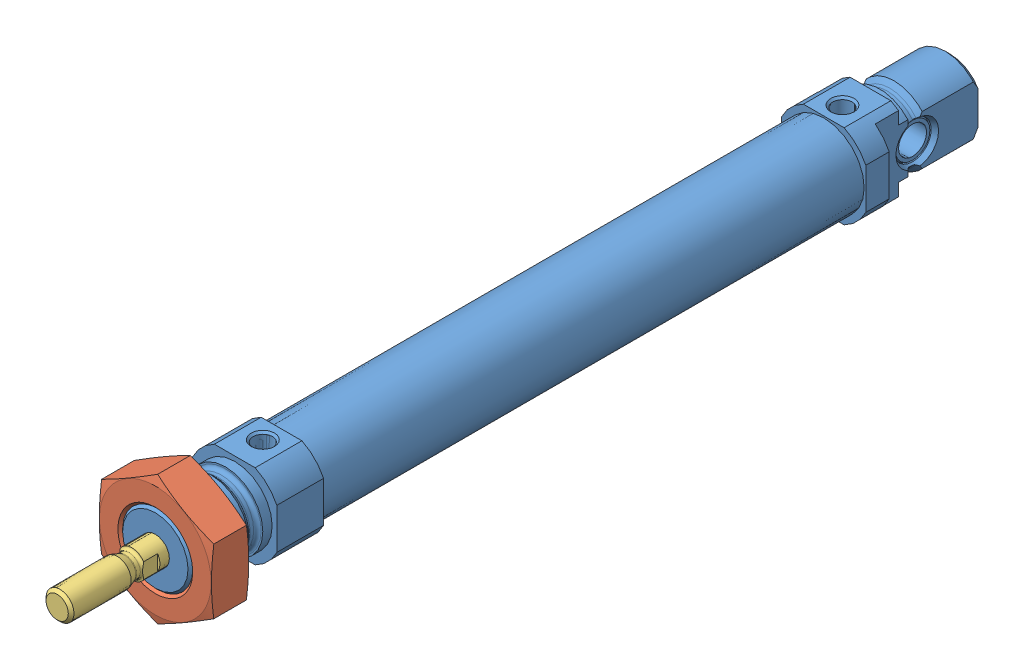
SolidWorks assembly 19202_DSNU_16_80_P_A____0_, configuration Default. Lengths in mm.
Overall size (24 27.71 191).
3 component instances, 3 part files, 6 mates.
Components (placement in the parent):
- 19202_DSNU_16_80_P____A____0_ZR_-1: 19202_DSNU_16_80_P____A____0_ZR_ [Default] x (0 0 -1) z (1 0 0)
- DIN_439_B___M16x1_5_F_-1: DIN_439_B___M16x1_5_F_ [Default] x (-1 0 0) z (0 1 0)
- 19202_DSNU_16_80_P____A___00__0_KS_-1: 19202_DSNU_16_80_P____A___00__0_KS_ [Default] x (-1 0 0) z (0 0 1)
Mates (geometry in assembly coordinates):
- Distance3: distance = 4 mm: plane of 19202_DSNU_16_80_P____A____0_ZR_-1 through (0 0 -8) normal (0 0 -1); plane of DIN_439_B___M16x1_5_F_-1
- Coincident1: coincident: line of 19202_DSNU_16_80_P____A____0_ZR_-1 through (0 0 -80.9) axis (0 0 1); line of DIN_439_B___M16x1_5_F_-1 through (0 0 50) axis (0 0 -1)
- Angle3: planar angle = 0 rad: plane of DIN_439_B___M16x1_5_F_-1; plane of 19202_DSNU_16_80_P____A____0_ZR_-1 through (0 0 0) normal (-1 0 0)
- LimitDistance1: limit distance = 0 mm: plane of 19202_DSNU_16_80_P____A____0_ZR_-1 through (0 0 0) normal (0 0 1); plane of 19202_DSNU_16_80_P____A___00__0_KS_-1 through (0 0 0) normal (0 0 -1)
- Coincident2: coincident: line of 19202_DSNU_16_80_P____A____0_ZR_-1 through (0 0 80.9) axis (0 0 -1); line of 19202_DSNU_16_80_P____A___00__0_KS_-1 through (0 0 -80.9) axis (0 0 1)
- Angle6: planar angle = 0 rad: plane of 19202_DSNU_16_80_P____A___00__0_KS_-1; plane of 19202_DSNU_16_80_P____A____0_ZR_-1 through (0 0 0) normal (-1 0 0)
